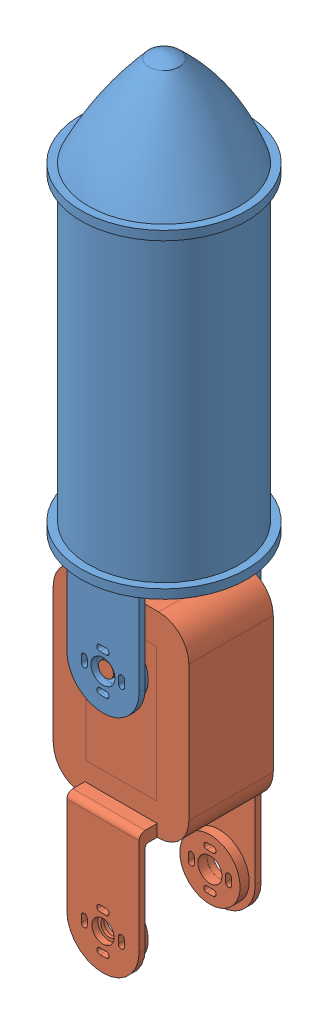
SolidWorks assembly test_2, configuration 預設. Lengths in mm.
Overall size (133 254.68 55).
2 component instances, 2 part files, 7 mates.
Components (placement in the parent):
- base_link2-1: base_link2 [預設] at origin size (55 179.98 55)
- link55-6: link55 [預設] at (0 -157.7 0) x (0 1 0) z (0 0 -1) size (107 45 40.5)
Mates (geometry in assembly coordinates):
- 平行相距2: distance = 50 mm: plane of assembly through (0 0 0) normal (0 1 0); plane of base_link2-1 through (0 50 -0.25) normal (0 -1 0)
- 平行相距3: distance = 12 mm: plane of assembly through (0 0 0) normal (1 0 0); plane of base_link2-1 through (-12 -53 18) normal (-1 0 0)
- 平行相距4: distance = 18.5 mm: plane of assembly through (0 0 0) normal (0 0 1); plane of base_link2-1 through (0 -83 -18.5) normal (0 0 1)
- 同軸心4: concentric: cylinder of base_link2-1 through (0 -83 -20.5) axis (0 0 1) radius 4; cylinder of link55-6 through (0 -83 -19) axis (0 0 1) radius 2.5
- 同軸心5: concentric: cylinder of base_link2-1 through (0 -83 19) axis (0 0 -1) radius 4; cylinder of link55-6 through (0 -83 14) axis (0 0 1) radius 2.5
- 平行3: parallel: plane of base_link2-1 through (-12 -53 18) normal (-1 0 0); plane of link55-6
- 平行相距9: distance = 1 mm: plane of link55-6 through (0 -67.7653 14) normal (0 0 1); plane of base_link2-1 through (0 -83 15) normal (0 0 -1)
